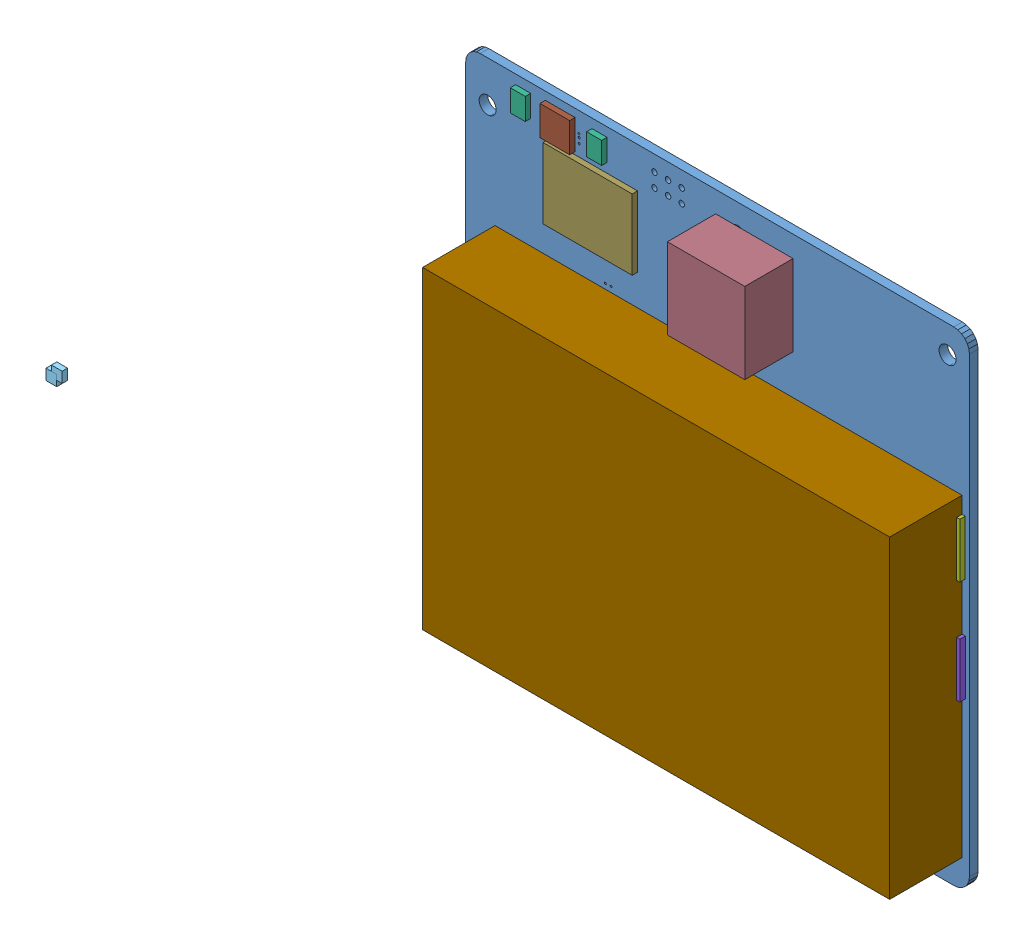
SolidWorks assembly pandasat_payload, configuration Défaut. Lengths in mm.
Overall size (171.13 92.27 15.1).
19 component instances, 15 part files, 0 mates.
Components (placement in the parent):
- pandasat_payload-1: pandasat_payload [Défaut] at origin size (93.89 90.17 1.6)
- 0603CAP_10PF-1: 0603CAP_10PF [Défaut] at (24.048 41.0246 1.6) x (0 1 0) z (0 0 1) size (3 1.99 1)
- 0603CAP_10PF-2: 0603CAP_10PF [Défaut] at (20.9072 37.8172 1.6) x (-1 0 0) z (0 0 1) size (3 1.99 1)
- 0603CAP_10NF-1: 0603CAP_10NF [Défaut] at (23.9876 37.8218 1.6) x (-1 0 0) z (0 0 1) size (3 1.99 1)
- 0603CAP_0_1UF-1: 0603CAP_0_1UF [Défaut] at (29.3398 27.838 1.6) size (3 1.99 1)
- DUMMY_FRAMELETTERNO_PACKAGE-1: DUMMY_FRAMELETTERNO_PACKAGE [Défaut] at (-75.23 -0.08 1.6) size (2 2 1)
- DUMMY_FRAMELETTERNO_PACKAGE-2: DUMMY_FRAMELETTERNO_PACKAGE [Défaut] at (-76.24 -1.1 1.6) size (2 2 1)
- U_FL_U_FL-1: U_FL_U_FL [Défaut] at (25.04 86.46 1.6) x (-1 0 0) z (0 0 1) size (2.8 4.06 1)
- U_FL_U_FL-2: U_FL_U_FL [Défaut] at (10.6 86.38 1.6) size (2.8 4.06 1)
- 1X04_J2_1X04-1: 1X04_J2_1X04 [Défaut] at (91.83 51.79 1.6) x (0 1 0) z (0 0 1) size (10.16 2.64 1)
- 1X04_J3_1X04-1: 1X04_J3_1X04 [Défaut] at (91.8464 32.4358 1.6) x (0 1 0) z (0 0 1) size (10.16 2.64 1)
- 2X3_FEMALE-1: 2X3_FEMALE [Défaut] at (35.179 84.709 1.6) size (7.72 5.42 0)
- 2X3_FEMALE-2: 2X3_FEMALE [Défaut] at (39.7066 75.0208 1.6) x (0 -1 0) z (0 0 1) size (7.72 5.42 0)
- RPI3_RPI3RPI3-1: RPI3_RPI3RPI3 [Défaut] at (5.52 7.77 1.6) size (87.06 58.5 13.5)
- SO016_CH340G-1: SO016_CH340G [Défaut] at (24.01 32.53 1.6) x (-1 0 0) z (0 0 1) size (10.62 6.67 1)
- QFN325X5MM_EP2W_-1: QFN325X5MM_EP2W_ [Défaut] at (17.75 86.05 1.6) x (0 1 0) z (0 0 1) size (5.53 5.53 1)
- S1216_24PIN_PACKAGE_S1216V8-1: S1216_24PIN_PACKAGE_S1216V8 [Défaut] at (22.78 75.95 1.6) x (0 1 0) z (0 0 1) size (13.13 16.63 1)
- PN87520_PN87520-1: PN87520_PN87520 [Défaut] at (50.7014 78.7004 1.6) x (0 1 0) z (0 0 1) size (15.05 14.43 9)
- CRYSTALSMD3_2X2_5_12MHZ-1: CRYSTALSMD3_2X2_5_12MHZ [Défaut] at (21.02 40.9742 1.6) x (-1 0 0) z (0 0 1) size (3.26 2.63 1)
